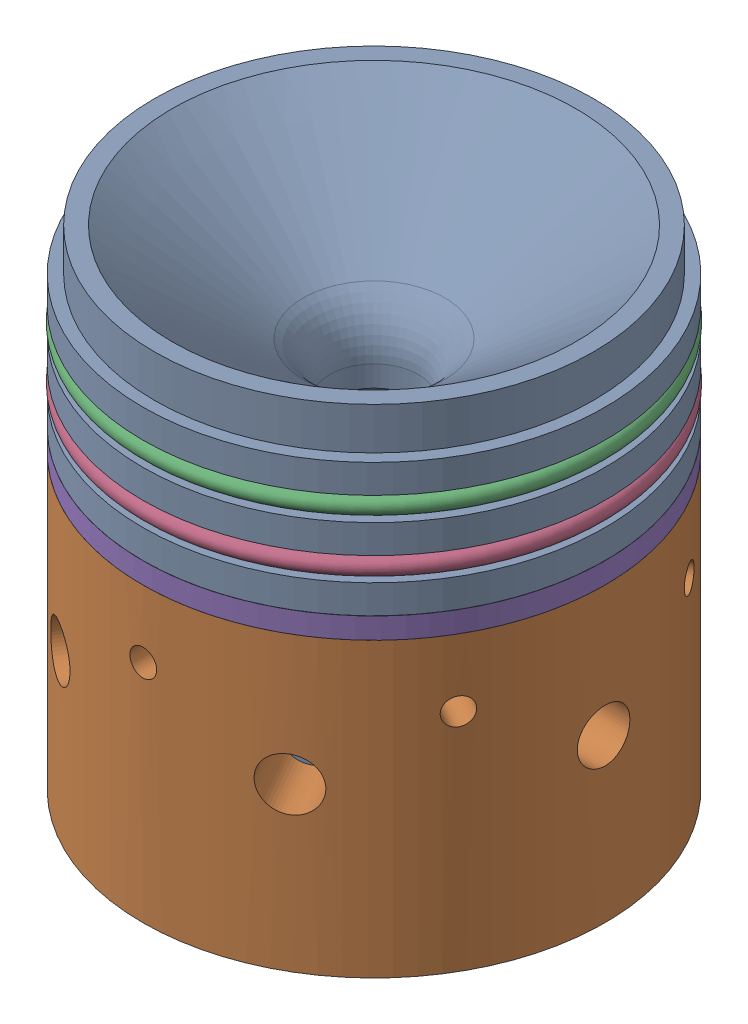
SolidWorks assembly 01_Nozzle_Assembly_GOW75SUST23_V2.0, configuration Default. Lengths in mm.
Overall size (81.34 73.79 81.34).
5 component instances, 4 part files, 7 mates.
Components (placement in the parent):
- Nozzle_GOW75SUST_V2.0-1: Nozzle_GOW75SUST_V2.0 [Default] at origin size (69.8 73.79 69.8)
- Nozzle_Retainer_GOW75SUST23_V2.0-1: Nozzle_Retainer_GOW75SUST23_V2.0 [Default] at (0 -50.9273 0) size (69.8 44.17 69.8)
- 9396K165_ORing_GOW75SUST23_V2.0-2: 9396K165_ORing_GOW75SUST23_V2.0 [9396K165] at (0 10.3349 0) x (0.997032 0 0.076983) z (0 -1 0) size (70 70 2.62)
- 9396K165_ORing_GOW75SUST23_V2.0-3: 9396K165_ORing_GOW75SUST23_V2.0 [9396K165] at (0 2.3737 0) x (0.984045 0 -0.177922) z (0 -1 0) size (70 70 2.62)
- Phenolic_Ring_GOW75SUST_V2.0-1: Phenolic_Ring_GOW75SUST_V2.0 [Default] at (0 -6.7567 0) size (69.8 3.17 69.8)
Mates (geometry in assembly coordinates):
- Concentric1: concentric anti-aligned: circle of Monolithic_Graphite_GOW75BSTR_V1.0-1; circle of Nozzle_Retainer_GOW75BSTR23_V2.0-1
- Concentric2: concentric anti-aligned: circle of Monolithic_Graphite_GOW75BSTR_V1.0-1; circle of Nozzle_Retainer_GOW75BSTR23_V2.0-1
- Coincident1: coincident aligned: plane of Monolithic_Graphite_GOW75BSTR_V1.0-1 through (-25.3996 -50.9273 0) normal (0 -1 0); plane of Nozzle_Retainer_GOW75BSTR23_V2.0-1 through (-34.8996 -50.9273 0) normal (0 -1 0)
- Concentric3: concentric anti-aligned: cylinder of Monolithic_Graphite_GOW75BSTR_V1.0-1 through (0 0 0) axis (0 1 0) radius 32.8672; circle of 9396K165_ORing-2
- Concentric4: concentric anti-aligned: cylinder of Monolithic_Graphite_GOW75BSTR_V1.0-1 through (0 0 0) axis (0 1 0) radius 32.8672; circle of 9396K165_ORing-3
- Coincident3: coincident anti-aligned: plane of Nozzle_Retainer_GOW75BSTR23_V2.0-1 through (-34.8996 -6.7567 0) normal (0 1 0); plane of Phenolic_Ring_GOW75SUST_V2.0-1 through (-34.8996 -6.7567 0) normal (0 -1 0)
- Concentric6: concentric aligned: circle of Nozzle_Retainer_GOW75BSTR23_V2.0-1; circle of Nozzle_Phenolic_Disk-1
